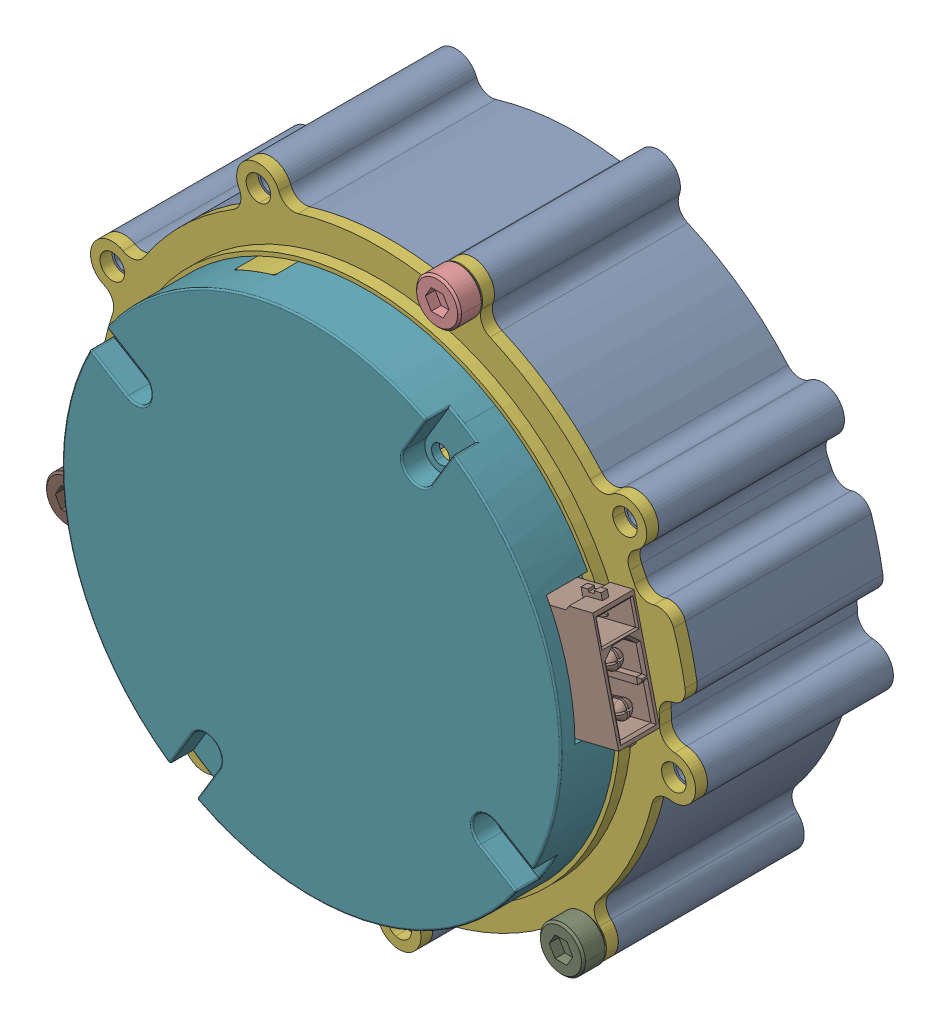
SolidWorks assembly ASM0002_ASM_1_ASM_1_ASM.stp, configuration 默认. Lengths in mm.
Overall size (96.28 96.17 36.5).
16 component instances, 9 part files, 0 mates.
Components (placement in the parent):
- 0714_ASM_1_ASM_1_ASM_1_ASM.stp-1: 0714_ASM_1_ASM_1_ASM_1_ASM.stp [默认] at origin size (96.28 96.17 36.5)
  - 3_1_02_067_0003_ASM_ASM_1_ASM_1_ASM.stp-1: 3_1_02_067_0003_ASM_ASM_1_ASM_1_ASM.stp [默认] at origin size (96.28 96.17 36.5)
    - 3_1_02_067_0003_ASM_1_ASM_1_ASM_ASM.stp-1: 3_1_02_067_0003_ASM_1_ASM_1_ASM_ASM.stp [默认] at origin size (96.28 96.17 36.5)
      - 1_1_06_EB673-504_1_1_1_1_1.stp-1: 1_1_06_EB673-504_1_1_1_1_1.stp [默认] at (39.8324 39.833 -22) size (79.19 78.95 25.5)
      - 1_2_04_670601_1_1_1_1_1.stp-1: 1_2_04_670601_1_1_1_1_1.stp [默认] at (93.9161 79.9966 -44) size (37 37 4)
      - 1_1_02_EB671-500_1_1_1_1_1.stp-1: 1_1_02_EB671-500_1_1_1_1_1.stp [默认] at (93.9161 79.9966 -44.4) x (-0.960973 0.276644 0) z (0 0 1) size (33 33 8.5)
      - 1_2_04_694000_1_1_1_1_1.stp-1: 1_2_04_694000_1_1_1_1_1.stp [默认] at (93.9161 79.9966 -44.5) size (11 11 4)
      - 1_2_06_000213_1_1_1_1_1.stp-1: 1_2_06_000213_1_1_1_1_1.stp [默认] at (93.9161 79.9966 -45.5) size (38.8 36.2 1.5)
      - 1_1_31_QT-642_1_1_1_1_1.stp-1: 1_1_31_QT-642_1_1_1_1_1.stp [默认] at (93.9161 79.9966 -22) x (-0.970555 -0.24088 0) z (0 0 -1) size (79.5 79.36 6)
      - 1_1_06_EB673-502_1_1_1_1_1.stp-1: 1_1_06_EB673-502_1_1_1_1_1.stp [默认] at (93.9161 79.9966 -13) x (-0.515958 -0.856614 0) z (0 0 -1) size (63 63 8)
    - 0518_ASM_2_ASM_1_ASM_1_ASM_1_AS_ASM.stp-1: 0518_ASM_2_ASM_1_ASM_1_ASM_1_AS_ASM.stp [默认] at (93.9161 79.9966 -17.235) x (0.235897 -0.971778 0) z (0 0 1) size (15.5 11.3 5.2)
      - 12345_ASM_1_ASM_2_ASM_1_ASM_1_A_ASM.stp-1: 12345_ASM_1_ASM_2_ASM_1_ASM_1_A_ASM.stp [默认] at origin size (15.5 11.3 5.2)
        - DUANZI_1_3_1_1_1_1_1_1.stp-1: DUANZI_1_3_1_1_1_1_1_1.stp [默认] at (-0.1798 16.5474 0.4329) x (0 0 -1) z (0 1 0) size (5.2 15.5 11.3)
- LUODING_1_1.stp-1: LUODING_1_1.stp [默认] at (119.9375 52.9941 -20.5) x (-1 0 0) z (0 1 0) size (5.68 3 5.68)
- LUODING_1_1.stp-2: LUODING_1_1.stp [默认] at (104.2902 116.0331 -20.5) x (-1 0 0) z (0 1 0) size (5.68 3 5.68)
- LUODING_1_1.stp-3: LUODING_1_1.stp [默认] at (57.5205 70.9626 -20.5) x (-1 0 0) z (0 1 0) size (5.68 3 5.68)
